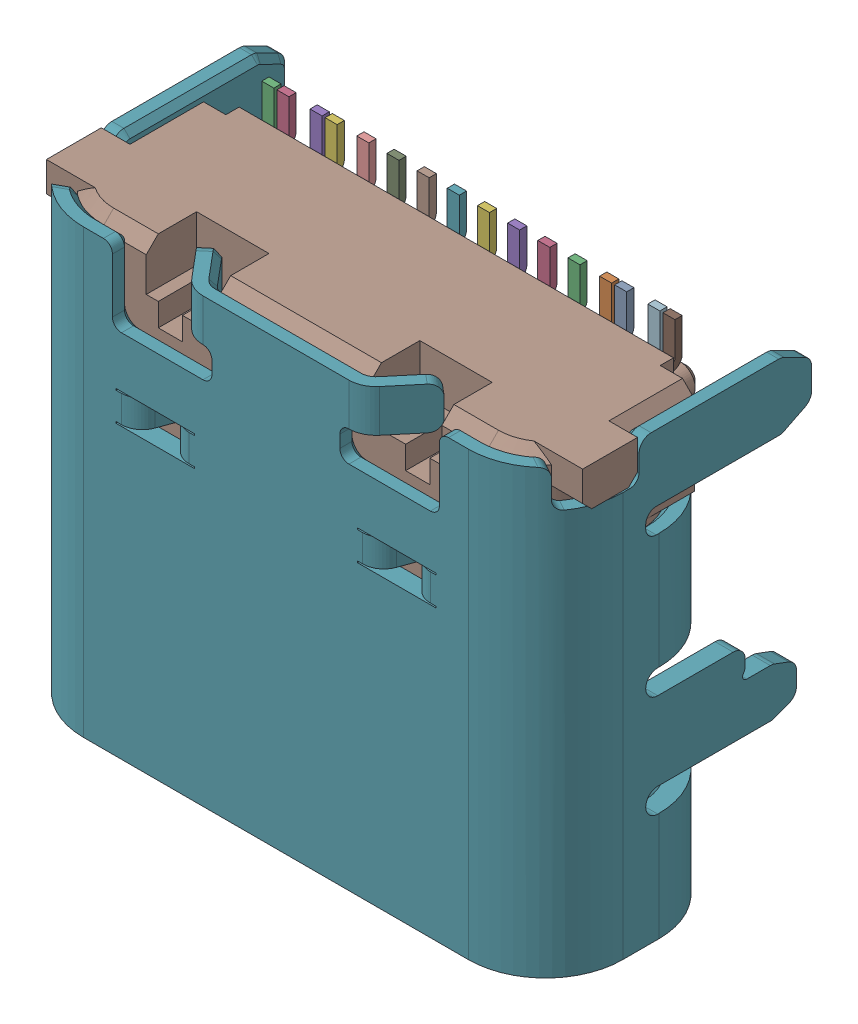
SolidWorks assembly Open CASCADE STEP translator 6.8 1.16.1, configuration Predeterminado. Lengths in mm.
Overall size (8.94 7.71 4.41).
46 component instances, 44 part files, 0 mates.
Components (placement in the parent):
- Body_1_5-1: Body_1_5 [Predeterminado] at (3.2 -4.8 0) x (1 0 0) z (0 -1 0) size (8.94 4.41 7.71)
  - Imported_2-1: Imported_2 [Predeterminado] at (0 0 -1.255) size (8.94 4.41 7.71)
    - SOLID_41-1: SOLID_41 [Predeterminado] at origin size (0.25 0.05 2.38)
    - SOLID_42-1: SOLID_42 [Predeterminado] at origin size (0.25 0.05 2.38)
    - SOLID_43-1: SOLID_43 [Predeterminado] at origin size (0.25 0.05 1.88)
    - SOLID_44-1: SOLID_44 [Predeterminado] at origin size (0.25 0.05 1.88)
    - SOLID_45-1: SOLID_45 [Predeterminado] at origin size (0.25 0.05 1.88)
    - SOLID_46-1: SOLID_46 [Predeterminado] at origin size (0.25 0.05 1.88)
    - SOLID_47-1: SOLID_47 [Predeterminado] at origin size (0.25 0.05 1.88)
    - SOLID_48-1: SOLID_48 [Predeterminado] at origin size (0.25 0.05 1.88)
    - SOLID_49-1: SOLID_49 [Predeterminado] at origin size (0.25 0.05 1.88)
    - SOLID_50-1: SOLID_50 [Predeterminado] at origin size (0.25 0.05 1.88)
    - SOLID_51-1: SOLID_51 [Predeterminado] at origin size (0.25 0.05 2.38)
    - SOLID_52-1: SOLID_52 [Predeterminado] at origin size (0.25 0.05 2.38)
    - SOLID_53-1: SOLID_53 [Predeterminado] at origin size (0.25 0.05 2.38)
    - SOLID_54-1: SOLID_54 [Predeterminado] at origin size (0.25 0.05 1.88)
    - SOLID_55-1: SOLID_55 [Predeterminado] at origin size (0.25 0.05 1.88)
    - SOLID_56-1: SOLID_56 [Predeterminado] at origin size (0.25 0.05 2.38)
    - SOLID_57-1: SOLID_57 [Predeterminado] at origin size (0.25 0.05 1.88)
    - SOLID_58-1: SOLID_58 [Predeterminado] at origin size (0.25 0.05 1.88)
    - SOLID_59-1: SOLID_59 [Predeterminado] at origin size (0.25 0.05 1.88)
    - SOLID_60-1: SOLID_60 [Predeterminado] at origin size (0.25 0.05 1.88)
    - SOLID_61-1: SOLID_61 [Predeterminado] at origin size (0.25 0.05 2.38)
    - SOLID_62-1: SOLID_62 [Predeterminado] at origin size (0.25 0.05 1.88)
    - SOLID_63-1: SOLID_63 [Predeterminado] at origin size (0.25 0.05 1.88)
    - SOLID_64-1: SOLID_64 [Predeterminado] at origin size (0.25 0.05 2.38)
    - SOLID_65-1: SOLID_65 [Predeterminado] at origin size (0.35 0.1 1.82)
    - SOLID_66-1: SOLID_66 [Predeterminado] at origin size (0.35 0.1 1.82)
    - SOLID_67-1: SOLID_67 [Predeterminado] at origin size (0.2 0.32 0.73)
    - SOLID_68-1: SOLID_68 [Predeterminado] at origin size (0.2 0.32 0.73)
    - SOLID_69-1: SOLID_69 [Predeterminado] at origin size (0.2 0.32 0.73)
    - SOLID_70-1: SOLID_70 [Predeterminado] at origin size (0.2 0.32 0.73)
    - SOLID_71-1: SOLID_71 [Predeterminado] at origin size (0.2 0.32 0.73)
    - SOLID_72-1: SOLID_72 [Predeterminado] at origin size (0.2 0.32 0.73)
    - SOLID_73-1: SOLID_73 [Predeterminado] at origin size (0.2 0.32 0.73)
    - SOLID_74-1: SOLID_74 [Predeterminado] at origin size (0.2 0.32 0.73)
    - SOLID_75-1: SOLID_75 [Predeterminado] at origin size (0.2 0.32 0.73)
    - SOLID_76-1: SOLID_76 [Predeterminado] at origin size (0.2 0.32 0.73)
    - SOLID_77-1: SOLID_77 [Predeterminado] at origin size (0.2 0.32 0.73)
    - SOLID_78-1: SOLID_78 [Predeterminado] at origin size (0.2 0.32 0.73)
    - SOLID_79-1: SOLID_79 [Predeterminado] at origin size (0.2 0.32 0.73)
    - SOLID_80-1: SOLID_80 [Predeterminado] at origin size (0.2 0.32 0.73)
    - SOLID_81-1: SOLID_81 [Predeterminado] at origin size (0.2 0.32 0.73)
    - SOLID_82-1: SOLID_82 [Predeterminado] at origin size (0.2 0.32 0.73)
    - SOLID_83-1: SOLID_83 [Predeterminado] at origin size (8.94 4.41 7.34)
    - SOLID_84-1: SOLID_84 [Predeterminado] at origin size (8.89 3.61 6.57)
